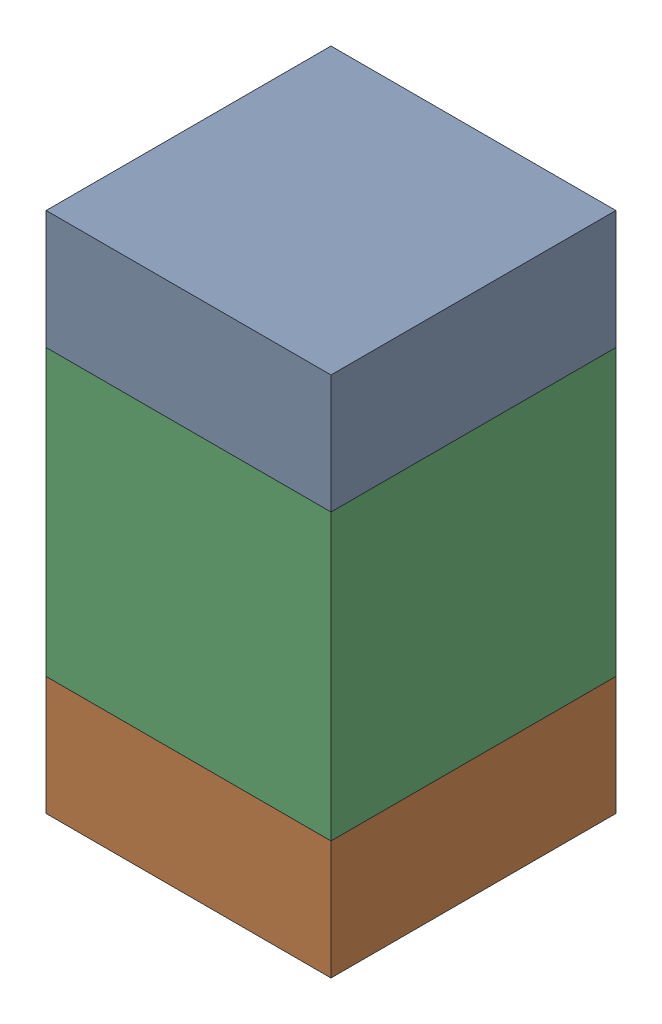
SolidWorks assembly C104_2PCB, configuration Default. Lengths in mm.
Overall size (0.6 1.1 0.6).
6 component instances, 2 part files, 0 mates.
Components (placement in the parent):
- 854785296-1: 854785296 [Default] at (108.7 85.025 0) size (0.6 0.25 0.6)
  - Extruded_10-1: Extruded_10 [Default] at origin size (0.6 0.25 0.6)
- 854785296-2: 854785296 [Default] at (108.7 84.175 0) size (0.6 0.25 0.6)
  - Extruded_10-1: Extruded_10 [Default] at origin size (0.6 0.25 0.6)
- 761606048-1: 761606048 [Default] at (108.7 84.6 0) size (0.6 0.6 0.6)
  - Extruded_9-1: Extruded_9 [Default] at origin size (0.6 0.6 0.6)
